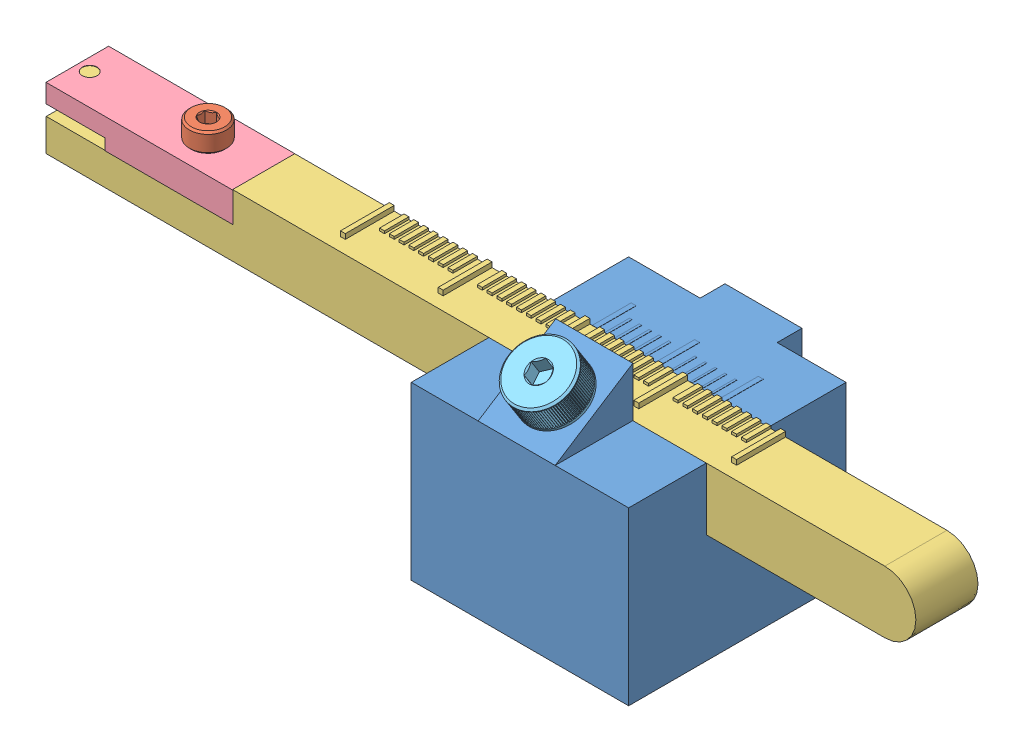
SolidWorks assembly headbar finished flipped, configuration Default. Lengths in mm.
Overall size (88.9 24.86 25.74).
6 component instances, 5 part files, 4 mates.
Components (placement in the parent):
- bar rest-1: bar rest [Default] at origin size (22.23 22.61 24.77)
- 91292A003_TYPE 18-8 SS SOCKET HEAD CAP SCREW-1: 91292A003_TYPE 18-8 SS SOCKET HEAD CAP SCREW [91292A003] at (-31.8888 5.7455 0) x (1 0 0) z (0 -1 0) size (3.8 3.8 5.09)
- headbar-1: headbar [Default] at (-93.8022 -57.3797 49.0764) x (0 0 -1) z (1 0 0) size (6.4 6.86 88.9)
  - headpost holder-1: headpost holder [Default] at (49.0764 62.9677 48.5529) x (0 1 0) z (0 0 1) size (6.86 6.35 88.9)
  - holder piece little-1: holder piece little [Default] at (49.0764 64.2202 58.1033) x (0 0 1) z (-1 0 0) size (19.1 3.05 6.4)
- 96125A301_NICKEL ALLOY SHOULDER SCREW-1: 96125A301_NICKEL ALLOY SHOULDER SCREW [96125A301] at (10.7798 13.9746 8.8593) x (0.978373 0.111501 -0.174221) z (0 0.842271 0.539054) size (6.35 6.35 10.69)
Mates (geometry in assembly coordinates):
- Concentric4: concentric anti-aligned: circle of 91292A003_TYPE 18-8 SS SOCKET HEAD CAP SCREW-1; circle of headbar-1/holder piece little-1
- Coincident3: coincident anti-aligned: plane of 91292A003_TYPE 18-8 SS SOCKET HEAD CAP SCREW-1 through (-31.8888 8.7455 0) normal (0 -1 0); plane of headbar-1/holder piece little-1 through (-35.6988 8.7455 0) normal (0 1 0)
- Concentric5: concentric anti-aligned: circle of bar rest-1; circle of 96125A301_NICKEL ALLOY SHOULDER SCREW-1
- Coincident6: coincident anti-aligned: plane of bar rest-1 through (-0.001 8.763 11.1125) normal (0 0.842271 0.539054); plane of 96125A301_NICKEL ALLOY SHOULDER SCREW-1 through (11.4365 9.626 9.7641) normal (0 -0.842271 -0.539054)
